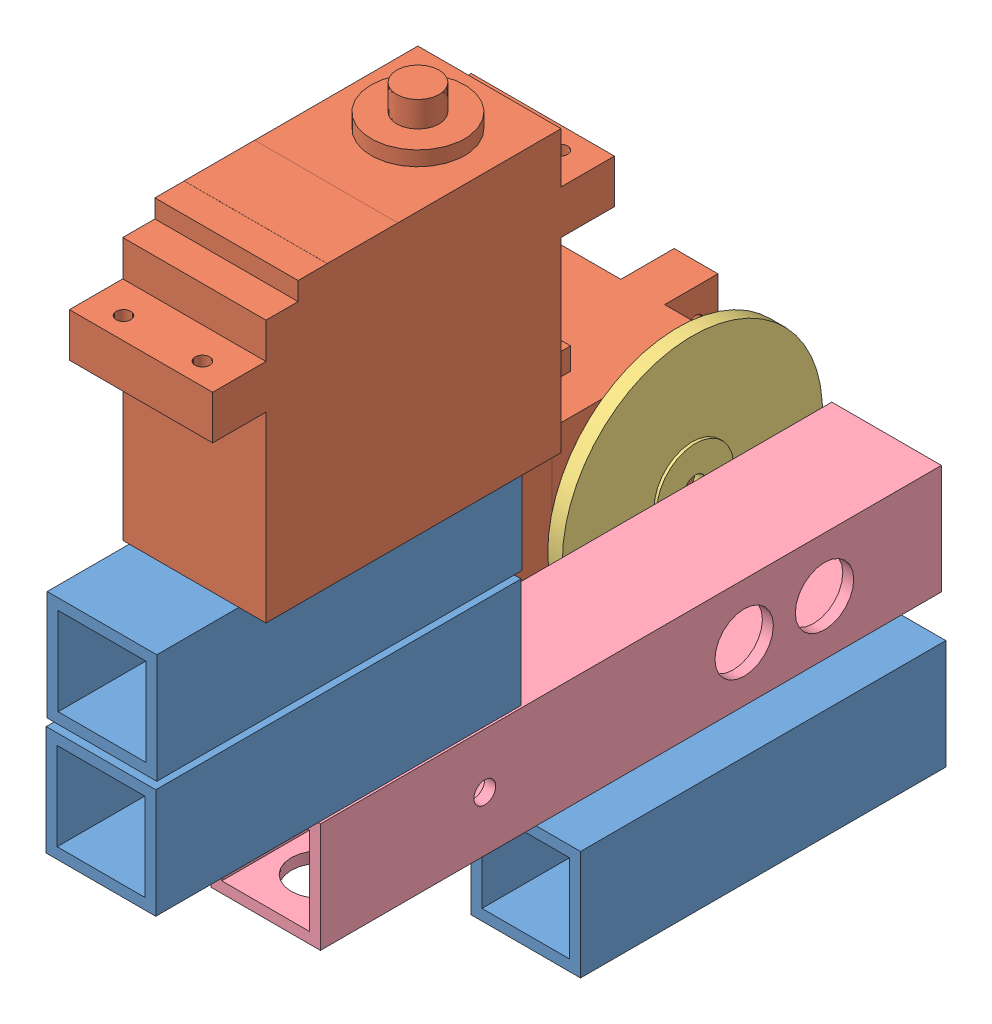
SolidWorks assembly 刀1, configuration ﾃﾞﾌｫﾙﾄ. Lengths in mm.
Overall size (71.04 112.32 112.6).
7 component instances, 4 part files, 2 mates.
Components (placement in the parent):
- 角_15_15_1.5-1: 角_15_15_1.5 [ﾃﾞﾌｫﾙﾄ] at (-6.6581 -1.5886 25) size (15 15 50)
- サーボ_MG995-1: サーボ_MG995 [ﾃﾞﾌｫﾙﾄ] at (-29.3244 59.5633 102.8913) x (1 0 0) z (0 1 0) size (19.6 55 43.9)
- サーボ_MG995-2: サーボ_MG995 [ﾃﾞﾌｫﾙﾄ] at (-64.9007 46.346 49.1779) x (0 -1 0) z (1 0 0) size (19.6 55 43.9)
- サーボ_円盤-1: サーボ_円盤 [ﾃﾞﾌｫﾙﾄ] at (-21.8007 20.6814 38.5547) x (0 0 -1) z (1 0 0) size (35.6 35.6 5.1)
- 腕_刀_伸ばし-1: 腕_刀_伸ばし [ﾃﾞﾌｫﾙﾄ] at (-6.3762 19.7611 25.8848) size (15 15 85)
- 角_15_15_1.5-2: 角_15_15_1.5 [ﾃﾞﾌｫﾙﾄ] at (-6.4428 35.0074 83.3568) size (15 15 50)
- 角_15_15_1.5-3: 角_15_15_1.5 [ﾃﾞﾌｫﾙﾄ] at (-6.3621 51.0245 83.2967) size (15 15 50)
Mates (geometry in assembly coordinates):
- 同心円1: concentric anti-aligned: circle of サーボ_MG995-2; circle of サーボ_円盤-1
- 一致2: coincident anti-aligned: plane of サーボ_MG995-2 through (-24.5007 20.6814 38.5547) normal (1 0 0); plane of サーボ_円盤-1 through (-24.5007 20.6814 38.5547) normal (-1 0 0)
